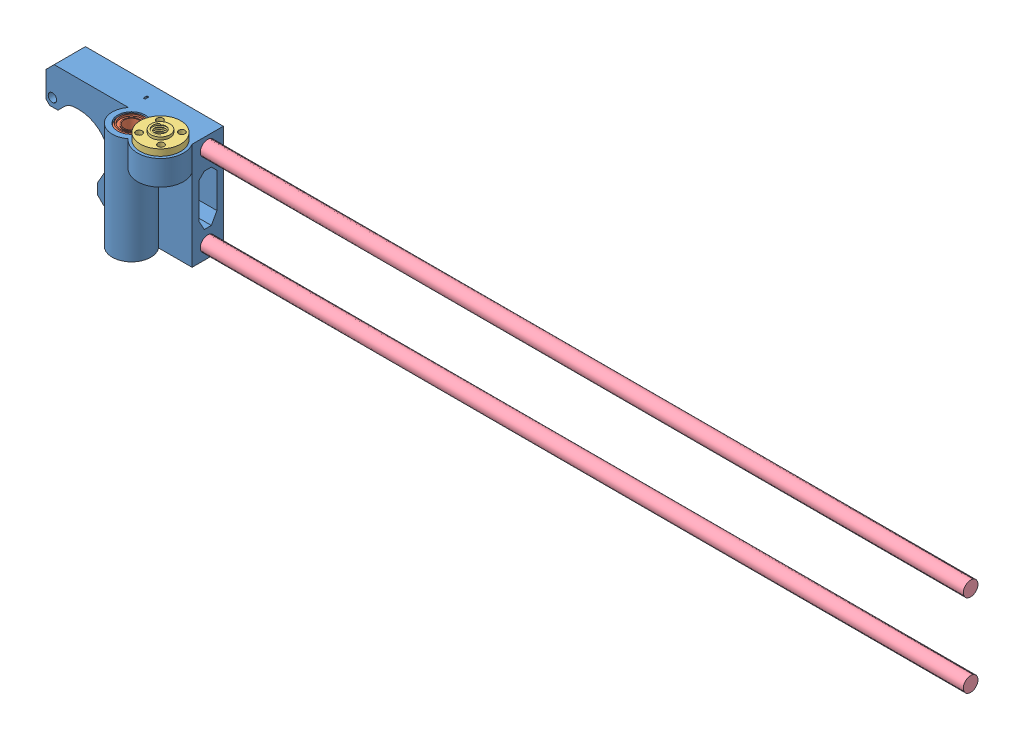
SolidWorks assembly Step6, configuration Default. Lengths in mm.
Overall size (494.45 65.59 39.05).
6 component instances, 4 part files, 10 mates.
Components (placement in the parent):
- Motor Mount-1: Motor Mount [Default] at (-5.2466 102.3397 79.6309) x (-1 0 0) z (0 0 -1) size (81.27 58 36)
- lm8uu-1: lm8uu [Default] at (-31.6736 56.3397 86.1309) x (0.992787 0 -0.119895) z (0 -1 0) size (15 15 24)
- lm8uu-2: lm8uu [Default] at (-31.6736 90.3397 86.1309) x (0.925343 0 -0.379132) z (0 -1 0) size (15 15 24)
- flanged lead screw nut-1: flanged lead screw nut [Default] at (-15.9237 105.8397 86.1309) x (0.725187 0 0.688552) z (0 -1 0) size (22 22 19.88)
- BedSlider-1: BedSlider [Default] at (-40.2466 92.2078 65.2897) x (0 -0.353265 -0.935523) z (1 0 0) size (8 8 450)
- BedSlider-2: BedSlider [Default] at (-40.2466 48.913 64.4001) x (0 -0.091311 -0.995822) z (1 0 0) size (8 8 450)
Mates (geometry in assembly coordinates):
- Concentric7: concentric: cylinder of Motor Mount-1 through (-15.9237 88.8397 86.1309) axis (0 1 0) radius 12.5; cylinder of flanged lead screw nut-1 through (-15.9237 105.8397 86.1309) axis (0 1 0) radius 11
- Concentric8: concentric: cylinder of Motor Mount-1 through (-31.6736 44.3397 86.1309) axis (0 1 0) radius 7.575; cylinder of lm8uu-1 through (-31.6736 44.3397 86.1309) axis (0 1 0) radius 7.5
- Concentric9: concentric: cylinder of Motor Mount-1 through (-31.6736 44.3397 86.1309) axis (0 1 0) radius 7.575; cylinder of lm8uu-2 through (-31.6736 78.3397 86.1309) axis (0 1 0) radius 7.5
- Coincident1: coincident anti-aligned: plane of Motor Mount-1 through (-5.2466 102.3397 62.6309) normal (0 1 0); plane of flanged lead screw nut-1 through (-7.9466 102.3397 93.705) normal (0 -1 0)
- Coincident2: coincident aligned: plane of Motor Mount-1 through (-5.2466 44.3397 62.6309) normal (0 -1 0); plane of lm8uu-1 through (-31.6736 44.3397 86.1309) normal (0 -1 0)
- Coincident3: coincident aligned: plane of Motor Mount-1 through (-5.2466 102.3397 62.6309) normal (0 1 0); plane of lm8uu-2 through (-31.6736 102.3397 86.1309) normal (0 1 0)
- Concentric10: concentric: cylinder of Motor Mount-1 through (-40.2466 96.3397 71.1309) axis (1 0 0) radius 4.05; cylinder of BedSlider-1 through (409.7534 96.3397 71.1309) axis (-1 0 0) radius 4
- Concentric11: concentric: cylinder of Motor Mount-1 through (-40.2466 51.3397 71.1309) axis (1 0 0) radius 4.05; cylinder of BedSlider-2 through (409.7534 51.3397 71.1309) axis (-1 0 0) radius 4
- Coincident4: coincident anti-aligned: plane of Motor Mount-1 through (-40.2466 96.3397 71.1309) normal (1 0 0); plane of BedSlider-1 through (-40.2466 96.3397 71.1309) normal (-1 0 0)
- Coincident5: coincident anti-aligned: plane of Motor Mount-1 through (-40.2466 51.3397 71.1309) normal (1 0 0); plane of BedSlider-2 through (-40.2466 51.3397 71.1309) normal (-1 0 0)
